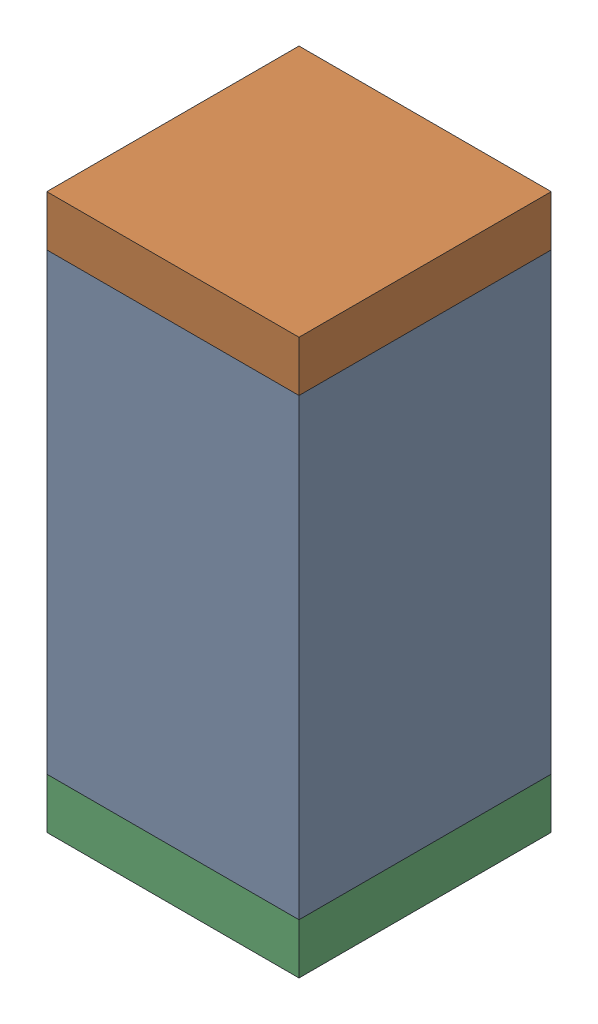
SolidWorks assembly C87, configuration Default. Lengths in mm.
Overall size (0.5 1.1 0.5).
6 component instances, 2 part files, 0 mates.
Components (placement in the parent):
- 791586336-1: 791586336 [Default] at (117.3 64.95 0) size (0.5 0.9 0.5)
  - Extruded_8-1: Extruded_8 [Default] at origin size (0.5 0.9 0.5)
- 810157360-1: 810157360 [Default] at (117.3 65.45 0) size (0.5 0.1 0.5)
  - Extruded_9-1: Extruded_9 [Default] at origin size (0.5 0.1 0.5)
- 810157360-2: 810157360 [Default] at (117.3 64.45 0) size (0.5 0.1 0.5)
  - Extruded_9-1: Extruded_9 [Default] at origin size (0.5 0.1 0.5)
